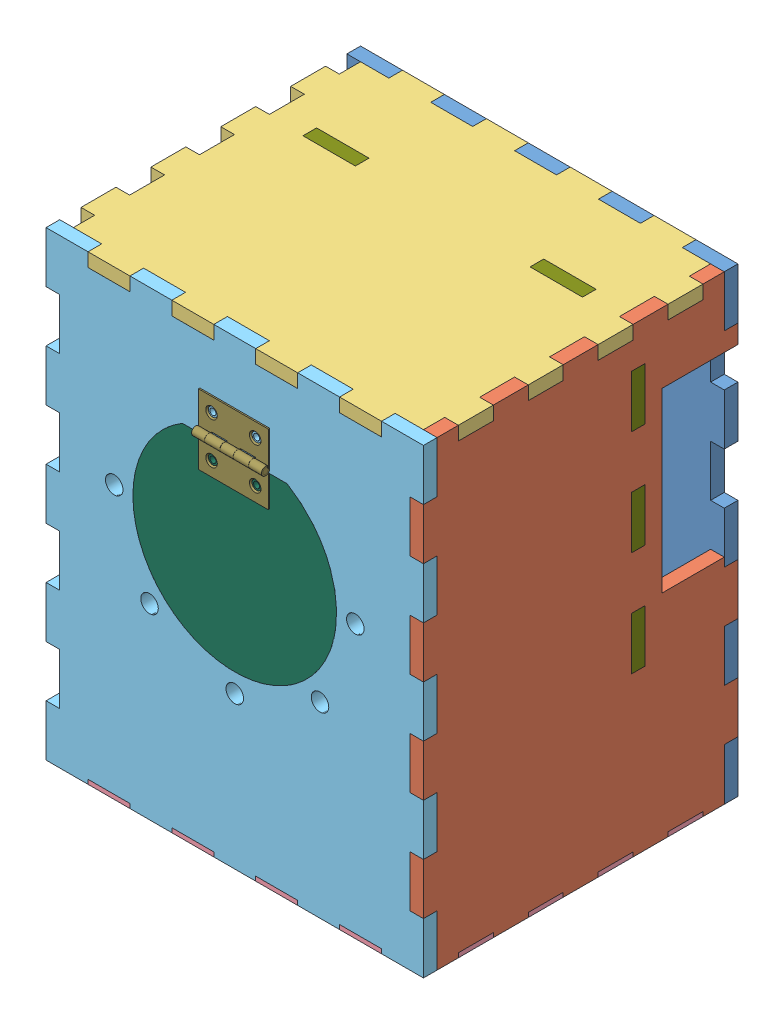
SolidWorks assembly useless_machine, configuration Default. Lengths in mm.
Overall size (137.17 170.24 117.3).
35 component instances, 17 part files, 47 mates.
Components (placement in the parent):
- useless_machine_bottom-1: useless_machine_bottom [Default] at (-6.0741 12.6617 113.5063) size (137.16 167.64 4.96)
- useless_machine_motor_side-2: useless_machine_motor_side [Default] at (57.545 12.6617 170.6562) x (0 1 0) z (1 0 0) size (167.64 114.3 4.96)
- useless_machine_motor_side-3: useless_machine_motor_side [Default] at (-74.6541 12.6617 170.6562) x (0 1 0) z (1 0 0) size (167.64 114.3 4.96) (hidden)
- useless_machine_side-1: useless_machine_side [Default] at (-6.0741 96.4817 170.6562) x (-1 0 0) z (0 -1 0) size (137.16 114.3 4.96)
- useless_machine_side_front-1: useless_machine_side_front [Default] at (-6.0741 -69.5708 170.6562) x (1 0 0) z (0 -1 0) size (137.16 114.3 1.59)
- useless_machine_lid-1: useless_machine_lid [Default] at (-6.0741 27.9017 222.8453) size (137.16 167.64 4.96)
- Servomotor SG 5010-1: Servomotor SG 5010 [Default] at (-13.9646 -11.9742 124.8788) x (-1 0 0) z (0 0.999962 -0.008727) size (54.4 42.11 20.33)
  - Tap 01-1: Tap 01 [Default] at (2.6095 0.3364 39.8745) x (1 0 0) z (0 -0.008727 -0.999962) size (41 6.5 20)
  - Tap 02-1: Tap 02 [Default] at (2.6095 20.3356 39.6999) x (1 0 0) z (0 -0.008727 -0.999962) size (41 20 20)
  - Tap 03-1: Tap 03 [Default] at (2.6095 20.3356 39.6999) x (-1 0 0) z (0 -0.008727 -0.999962) size (54.4 11.9 20)
  - Eje-1: Eje [Default] at (-7.8905 29.3353 39.6214) x (1 0 0) z (0 0.008727 0.999962) size (6 6.5 6)
  - pan head cross recess screw_iso-1: pan head cross recess screw_iso [ISO 7045 - M1.6 x 16 - Z - 16C] at (-15.5814 -5.9305 32.238) x (0 0.999962 -0.008727) z (0.720061 0.006055 0.693884) size (17.27 3.2 3.2)
  - pan head cross recess screw_iso-2: pan head cross recess screw_iso [ISO 7045 - M1.6 x 16 - Z - 16C] at (-15.5814 -5.7963 47.6192) x (0 0.999962 -0.008727) z (0.008727 0.008726 0.999924) size (17.27 3.2 3.2)
  - pan head cross recess screw_iso-3: pan head cross recess screw_iso [ISO 7045 - M1.6 x 16 - Z - 16C] at (20.8004 -5.7963 47.6192) x (0 0.999962 -0.008727) z (0.008727 0.008726 0.999924) size (17.27 3.2 3.2)
  - pan head cross recess screw_iso-4: pan head cross recess screw_iso [ISO 7045 - M1.6 x 16 - Z - 16C] at (20.8004 -5.9305 32.238) x (0 0.999962 -0.008727) z (0.008727 0.008726 0.999924) size (17.27 3.2 3.2)
- Servomotor SG 5010-2: Servomotor SG 5010 [Default] at (-24.477 55.9547 212.5931) x (0.975517 0.219922 0) z (-0.001919 0.008513 -0.999962) size (54.4 42.11 20.33)
  - Tap 01-1: Tap 01 [Default] at (2.6095 0.3364 39.8745) x (1 0 0) z (0 -0.008727 -0.999962) size (41 6.5 20)
  - Tap 02-1: Tap 02 [Default] at (2.6095 20.3356 39.6999) x (1 0 0) z (0 -0.008727 -0.999962) size (41 20 20)
  - Tap 03-1: Tap 03 [Default] at (2.6095 20.3356 39.6999) x (-1 0 0) z (0 -0.008727 -0.999962) size (54.4 11.9 20)
  - Eje-1: Eje [Default] at (-7.8905 29.3353 39.6214) x (1 0 0) z (0 0.008727 0.999962) size (6 6.5 6)
  - pan head cross recess screw_iso-1: pan head cross recess screw_iso [ISO 7045 - M1.6 x 16 - Z - 16C] at (-15.5814 -5.9305 32.238) x (0 0.999962 -0.008727) z (0.720061 0.006055 0.693884) size (17.27 3.2 3.2)
  - pan head cross recess screw_iso-2: pan head cross recess screw_iso [ISO 7045 - M1.6 x 16 - Z - 16C] at (-15.5814 -5.7963 47.6192) x (0 0.999962 -0.008727) z (0.008727 0.008726 0.999924) size (17.27 3.2 3.2)
  - pan head cross recess screw_iso-3: pan head cross recess screw_iso [ISO 7045 - M1.6 x 16 - Z - 16C] at (20.8004 -5.7963 47.6192) x (0 0.999962 -0.008727) z (0.008727 0.008726 0.999924) size (17.27 3.2 3.2)
  - pan head cross recess screw_iso-4: pan head cross recess screw_iso [ISO 7045 - M1.6 x 16 - Z - 16C] at (20.8004 -5.9305 32.238) x (0 0.999962 -0.008727) z (0.008727 0.008726 0.999924) size (17.27 3.2 3.2)
- Acople-1: Acople [Default] at (-6.0741 27.9017 162.7172) x (-0.187381 -0.982287 0) z (0.982287 -0.187381 0) size (20.6 5.65 20.6)
- 1603A230_SURFACE-MOUNT HINGE-1: 1603A230_SURFACE-MOUNT HINGE [1603A23] at (-6.0741 61.2386 229.3064) x (0 1 0) z (0 0 -1) size (25.4 25.4 3)
- OLED_27x27_r2-1: OLED_27x27_r2 [Default] at (-6.0131 -71.1583 137.9563) x (1 0 0) z (0 0 -1) size (27.3 9.22 27.3)
- 90272A077_ZINC-PLTD STL PAN HEAD PHILLIPS MACHINE SCREW-1: 90272A077_ZINC-PLTD STL PAN HEAD PHILLIPS MACHINE SCREW [90272A077] at (-16.3631 -65.8083 126.3563) x (0.729011 0 -0.684502) z (0 -1 0) size (4.24 4.24 8.15)
- 90272A077_ZINC-PLTD STL PAN HEAD PHILLIPS MACHINE SCREW-2: 90272A077_ZINC-PLTD STL PAN HEAD PHILLIPS MACHINE SCREW [90272A077] at (4.3369 -65.8083 149.5563) x (0.900627 0 0.434594) z (0 -1 0) size (4.24 4.24 8.15)
- 90272A077_ZINC-PLTD STL PAN HEAD PHILLIPS MACHINE SCREW-3: 90272A077_ZINC-PLTD STL PAN HEAD PHILLIPS MACHINE SCREW [90272A077] at (4.3369 -65.8083 126.3563) x (0.285424 0 -0.958401) z (0 -1 0) size (4.24 4.24 8.15)
- 90272A077_ZINC-PLTD STL PAN HEAD PHILLIPS MACHINE SCREW-4: 90272A077_ZINC-PLTD STL PAN HEAD PHILLIPS MACHINE SCREW [90272A077] at (-16.3631 -65.8083 149.5563) x (-0.64353 0 0.765421) z (0 -1 0) size (4.24 4.24 8.15)
- useless_machine_top_lid-1: useless_machine_top_lid [Default] at (-6.0741 27.9017 226.2188) size (74.05 68.78 1.59)
- servo_secure-1: servo_secure [Default] at (-6.0693 34.3708 149.7477) x (0 -1 0) z (0 0 1) size (119.26 137.17 4.96)
- Tap 03-1: Tap 03 [Default] at (-16.5741 27.9017 144.8672) x (1 0 0) z (0 -1 0) size (54.4 11.9 20)
- servo_arm-1: servo_arm [Default] at (-0.8165 0.218 199.6977) x (-0.435047 -0.650503 -0.622559) z (-0.882637 0.444788 0.152039) size (35.05 57.15 4.96)
Mates (geometry in assembly coordinates):
- Concentric6: concentric: cylinder of useless_machine_lid-1 through (-6.0741 27.9017 222.8453) axis (0 0 1) radius 37.0265; cylinder of Servomotor SG 5010-1/Eje-1 through (-6.0741 27.9017 154.8672) axis (0 0 1) radius 1.125
- Coincident75: coincident: plane of useless_machine_bottom-1 through (-6.0741 12.6617 118.4672) normal (0 0 1); plane of Servomotor SG 5010-1/Tap 01-1 through (-16.5741 27.9017 118.4672) normal (0 0 -1)
- Parallel11: parallel: plane of Servomotor SG 5010-1/Tap 02-1 through (3.9259 17.9017 124.8672) normal (1 0 0); plane of useless_machine_motor_side-2 through (62.5059 12.6617 170.6562) normal (1 0 0)
- Concentric7: concentric: cylinder of Servomotor SG 5010-1/Eje-1 through (-6.0741 27.9017 154.8672) axis (0 0 1) radius 1.125; cylinder of Acople-1 through (-6.0741 27.9017 160.3672) axis (0 0 1) radius 1.39
- Coincident77: coincident: plane of Servomotor SG 5010-1/Eje-1 through (-5.0433 30.5051 156.8672) normal (-0.373443 0.927653 0); plane of Acople-1 through (-5.0433 30.5051 157.0672) normal (0.373443 -0.927653 0)
- Coincident78: coincident: plane of Servomotor SG 5010-1/Eje-1 through (-6.0741 27.9017 160.3672) normal (0 0 1); plane of Acople-1 through (-6.0741 27.9017 160.3672) normal (0 0 -1)
- Coincident79: coincident: plane of Servomotor SG 5010-2/Tap 03-1 through (-35.3344 22.766 162.7172) normal (0 0 -1); plane of Acople-1 through (-6.0741 27.9017 162.7172) normal (0 0 1)
- Coincident82: coincident: plane of useless_machine_lid-1 through (-6.0741 27.9017 227.8062) normal (0 0 1); plane of 1603A230_SURFACE-MOUNT HINGE-1 through (6.6259 73.9386 227.8062) normal (0 0 -1)
- Concentric14: concentric: cylinder of useless_machine_lid-1 through (-14.0116 68.7792 222.8453) axis (0 0 1) radius 1.1049; cone of 1603A230_SURFACE-MOUNT HINGE-1 through (-14.0116 68.7792 228.3142) axis (0 0 -1)
- Concentric15: concentric: cylinder of useless_machine_lid-1 through (1.8634 68.7792 222.8453) axis (0 0 1) radius 1.1049; cone of 1603A230_SURFACE-MOUNT HINGE-1 through (1.8634 68.7792 228.3142) axis (0 0 -1)
- Coincident107: coincident: plane of useless_machine_side_front-1 through (-6.0741 -71.1583 170.6562) normal (0 -1 0); plane of OLED_27x27_r2-1 through (5.6369 -71.1583 126.3063) normal (0 1 0)
- Parallel13: parallel: plane of OLED_27x27_r2-1 through (-17.6631 -72.1583 151.6062) normal (0 0 1); plane of useless_machine_side_front-1 through (-74.6541 -71.1583 227.8062) normal (0 0 1)
- Distance2: distance = 76.2 mm: plane of useless_machine_side_front-1 through (-74.6541 -71.1583 227.8062) normal (0 0 1); plane of OLED_27x27_r2-1 through (-17.6631 -72.1583 151.6062) normal (0 0 1)
- Coincident114: coincident: plane of OLED_27x27_r2-1 through (5.6369 -72.1583 126.3063) normal (0 -1 0); plane of 90272A077_ZINC-PLTD STL PAN HEAD PHILLIPS MACHINE SCREW-1 through (-16.3631 -72.1583 126.3563) normal (0 1 0)
- Concentric17: concentric: circle of useless_machine_side_front-1; circle of 90272A077_ZINC-PLTD STL PAN HEAD PHILLIPS MACHINE SCREW-1
- Coincident116: coincident: plane of OLED_27x27_r2-1 through (5.6369 -72.1583 126.3063) normal (0 -1 0); plane of 90272A077_ZINC-PLTD STL PAN HEAD PHILLIPS MACHINE SCREW-3 through (4.3369 -72.1583 126.3563) normal (0 1 0)
- Concentric18: concentric: circle of useless_machine_side_front-1; circle of 90272A077_ZINC-PLTD STL PAN HEAD PHILLIPS MACHINE SCREW-3
- Concentric19: concentric: circle of useless_machine_side_front-1; circle of 90272A077_ZINC-PLTD STL PAN HEAD PHILLIPS MACHINE SCREW-2
- Coincident118: coincident: plane of OLED_27x27_r2-1 through (5.6369 -72.1583 126.3063) normal (0 -1 0); plane of 90272A077_ZINC-PLTD STL PAN HEAD PHILLIPS MACHINE SCREW-2 through (4.3369 -72.1583 149.5563) normal (0 1 0)
- Concentric20: concentric: circle of useless_machine_side_front-1; circle of 90272A077_ZINC-PLTD STL PAN HEAD PHILLIPS MACHINE SCREW-4
- Coincident119: coincident: plane of OLED_27x27_r2-1 through (5.6369 -72.1583 126.3063) normal (0 -1 0); plane of 90272A077_ZINC-PLTD STL PAN HEAD PHILLIPS MACHINE SCREW-4 through (-16.3631 -72.1583 149.5563) normal (0 1 0)
- Coincident127: coincident: plane of useless_machine_bottom-1 through (-6.0741 12.6617 113.5063) normal (0 0 -1); plane of useless_machine_side_front-1 through (-74.6541 -71.1583 113.5063) normal (0 0 -1)
- Coincident128: coincident: plane of useless_machine_bottom-1 through (-74.6541 -71.1583 118.4672) normal (0 -1 0); plane of useless_machine_side_front-1 through (-6.0741 -71.1583 170.6562) normal (0 -1 0)
- Coincident129: coincident: plane of useless_machine_bottom-1 through (-74.6541 -71.1583 118.4672) normal (-1 0 0); plane of useless_machine_side_front-1 through (-74.6541 -71.1583 113.5063) normal (-1 0 0)
- Coincident130: coincident: plane of useless_machine_bottom-1 through (-74.6541 96.4817 118.4672) normal (0 1 0); plane of useless_machine_side-1 through (-6.0741 96.4817 170.6562) normal (0 1 0)
- Coincident131: coincident: plane of useless_machine_bottom-1 through (-6.0741 12.6617 113.5063) normal (0 0 -1); plane of useless_machine_side-1 through (62.5059 91.5208 113.5063) normal (0 0 -1)
- Coincident132: coincident: plane of useless_machine_bottom-1 through (62.5059 -71.1583 118.4672) normal (1 0 0); plane of useless_machine_side-1 through (62.5059 91.5208 227.8062) normal (1 0 0)
- Distance3: distance = 54.991 mm: plane of OLED_27x27_r2-1 through (-19.6631 -72.1583 126.3063) normal (-1 0 0); plane of useless_machine_side_front-1 through (-74.6541 -71.1583 113.5063) normal (-1 0 0)
- Coincident143: coincident: plane of useless_machine_bottom-1 through (-6.0741 12.6617 113.5063) normal (0 0 -1); plane of useless_machine_motor_side-3 through (-69.6931 -71.1583 113.5063) normal (0 0 -1)
- Coincident144: coincident: plane of useless_machine_bottom-1 through (-74.6541 -71.1583 118.4672) normal (0 -1 0); plane of useless_machine_motor_side-3 through (-69.6931 -71.1583 113.5063) normal (0 -1 0)
- Coincident146: coincident: plane of useless_machine_bottom-1 through (-74.6541 -71.1583 118.4672) normal (-1 0 0); plane of useless_machine_motor_side-3 through (-74.6541 12.6617 170.6562) normal (-1 0 0)
- Coincident148: coincident: plane of useless_machine_bottom-1 through (62.5059 -71.1583 118.4672) normal (1 0 0); plane of useless_machine_motor_side-2 through (62.5059 12.6617 170.6562) normal (1 0 0)
- Coincident149: coincident: plane of useless_machine_bottom-1 through (-6.0741 12.6617 113.5063) normal (0 0 -1); plane of useless_machine_motor_side-2 through (62.5059 -71.1583 113.5063) normal (0 0 -1)
- Coincident150: coincident: plane of useless_machine_bottom-1 through (-74.6541 96.4817 118.4672) normal (0 1 0); plane of useless_machine_motor_side-2 through (62.5059 96.4817 113.5063) normal (0 1 0)
- Concentric21: concentric: cylinder of useless_machine_lid-1 through (-6.0741 27.9017 222.8453) axis (0 0 1) radius 37.0265; cylinder of useless_machine_top_lid-1 through (-6.0741 27.9017 227.8062) axis (0 0 -1) radius 37.0265
- Coincident151: coincident: plane of 1603A230_SURFACE-MOUNT HINGE-1 through (6.6259 48.5386 227.8062) normal (0 0 -1); plane of useless_machine_top_lid-1 through (-6.0741 27.9017 227.8062) normal (0 0 1)
- Coincident152: coincident: plane of useless_machine_motor_side-3 through (-74.6541 12.6617 170.6562) normal (-1 0 0); plane of useless_machine_lid-1 through (-74.6541 -71.1583 227.8062) normal (-1 0 0)
- Coincident153: coincident: plane of useless_machine_side_front-1 through (-6.0741 -71.1583 170.6562) normal (0 -1 0); plane of useless_machine_lid-1 through (-74.6541 -71.1583 227.8062) normal (0 -1 0)
- Coincident154: coincident: plane of useless_machine_motor_side-2 through (62.5059 -71.1583 227.8062) normal (0 0 1); plane of useless_machine_lid-1 through (-6.0741 27.9017 227.8062) normal (0 0 1)
- Tangent2: tangent: cylinder of Servomotor SG 5010-1/Eje-1 through (-6.0741 27.9017 154.8672) axis (0 0 1) radius 1.125; plane of Servomotor SG 5010-2/Tap 03-1 through (-15.2703 26.9818 172.7172) normal (0.219922 -0.975517 0)
- Distance5: distance = 17.78 mm: point of Servomotor SG 5010-2/Eje-1; cylinder of Servomotor SG 5010-1/Eje-1 through (-6.0741 27.9017 154.8672) axis (0 0 1) radius 1.125
- Coincident159: coincident: plane of Servomotor SG 5010-1/Tap 03-1 through (-16.5741 27.9017 144.8672) normal (0 0 -1); plane of Tap 03-1 through (-16.5741 27.9017 144.8672) normal (0 0 -1)
- Coincident160: coincident: plane of Servomotor SG 5010-1/Tap 03-1 through (10.6259 19.0517 147.2672) normal (1 0 0); plane of Tap 03-1 through (10.6259 19.0517 147.2672) normal (1 0 0)
- Coincident161: coincident: plane of Servomotor SG 5010-1/Tap 03-1 through (3.9259 19.0517 147.2672) normal (0 -1 0); plane of Tap 03-1 through (3.9259 19.0517 147.2672) normal (0 -1 0)
- Coincident167: coincident: plane of useless_machine_side-1 through (-6.0741 96.4817 170.6562) normal (0 1 0); plane of servo_secure-1 through (-6.0693 96.4817 149.7477) normal (0 1 0)
- Coincident170: coincident: plane of useless_machine_motor_side-2 through (62.5059 12.6617 170.6562) normal (1 0 0); plane of servo_secure-1 through (62.5059 34.3708 149.7477) normal (1 0 0)
- Coincident171: coincident: plane of servo_secure-1 through (-6.0693 34.3708 147.2672) normal (0 0 -1); plane of Tap 03-1 through (-16.5741 27.9017 147.2672) normal (0 0 1)
